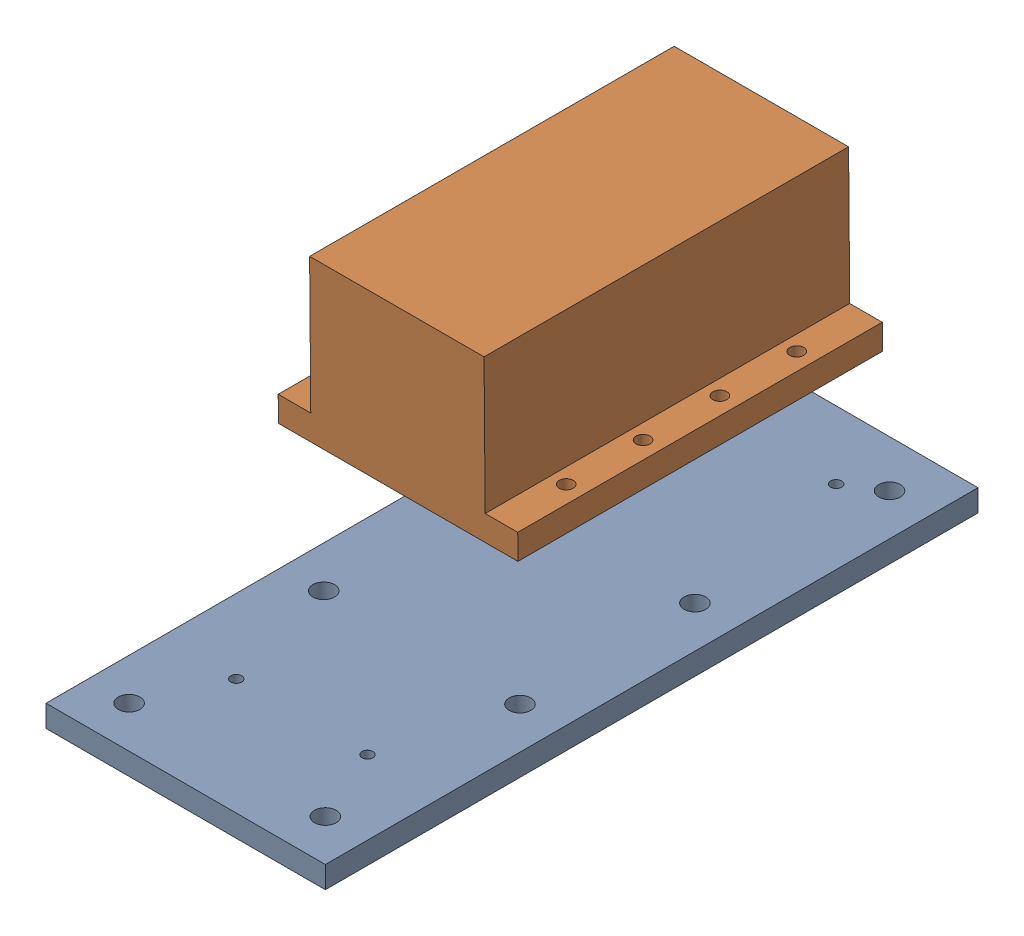
SolidWorks assembly Spindle_MOunted, configuration Default. Lengths in mm.
Overall size (235.52 152.81 400.94).
2 component instances, 2 part files, 0 mates.
Components (placement in the parent):
- Spindle Mounting Plate-1: Spindle Mounting Plate [Default] at (-89.0518 14.1983 132.1822) size (127.75 10 298.45)
- Spindle Mounting-1: Spindle Mounting [Default] at (-78.5554 92.3946 36.392) x (0.999978 0.005122 0.004225) z (-0.004208 -0.003315 0.999986) size (110 73.5 166)
